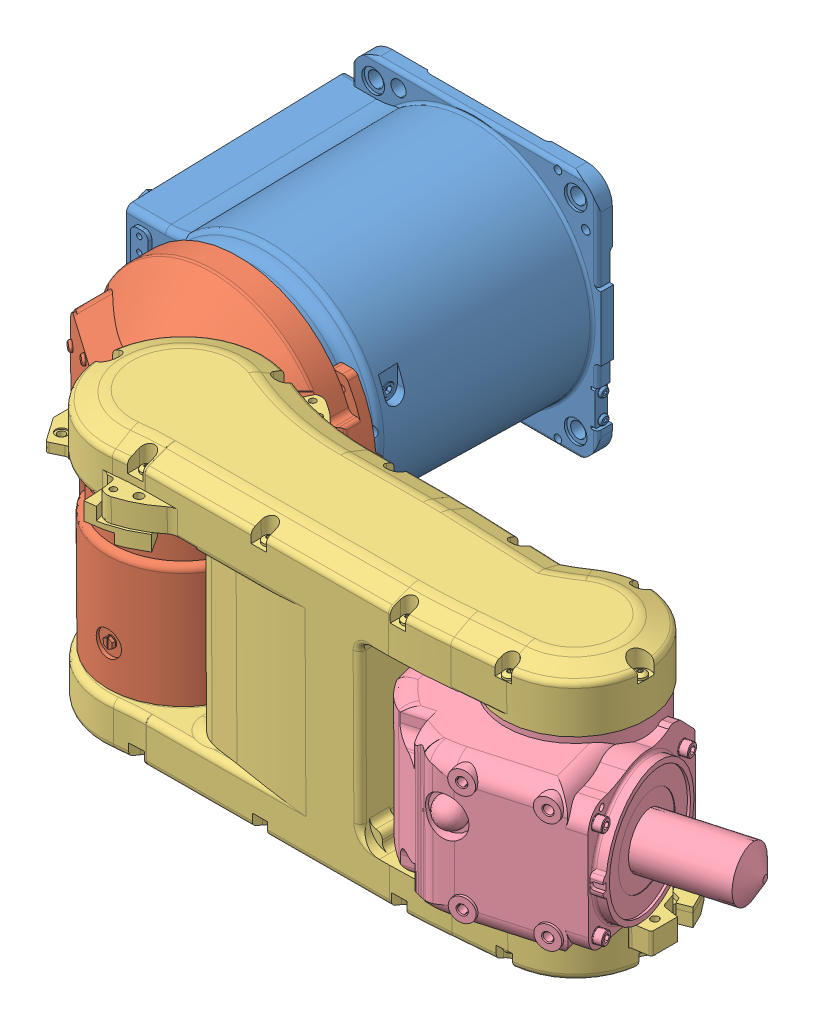
SolidWorks assembly EPSONS5_1, configuration Default. Lengths in mm.
Overall size (699.22 221.61 438.52).
4 component instances, 4 part files, 8 mates.
Components (placement in the parent):
- S5_BASE-1: S5_BASE [Default] at origin size (250.2 197 204.01)
- S5_ARM1-1: S5_ARM1 [Default] at (87.999 0.4259 126.5) x (0.999988 0.004839 0) z (-0.004839 0.999988 0) size (245.28 204.35 187)
- S5_ARM2-1: S5_ARM2 [Default] at (397.9856 3.926 126.6065) x (0.999988 0.004839 0.000344) z (-0.004839 0.999988 0) size (450 164.19 219.43)
- S5_ARM3-1: S5_ARM3 [Default] at (547.9742 6.6518 126.6061) x (0.999988 0.004839 -0.000003) z (0.000003 0 1) size (256.96 134.01 164.65)
Mates (geometry in assembly coordinates):
- Concentric4: concentric: cylinder of S5_BASE-1 through (0 0 -192.5) axis (0 0 1) radius 82
- Coincident4: coincident: plane of S5_BASE-1 through (0 0 0) normal (0 0 1)
- Coincident5: coincident anti-aligned: plane of S5_BASE-1 through (0 0 0) normal (0 0 1); plane of S5_ARM1-1 through (0 0 0) normal (0 0 -1)
- Concentric5: concentric aligned: cylinder of S5_BASE-1 through (0 0 -192.5) axis (0 0 1) radius 75; cylinder of S5_ARM1-1 through (0 0 -4.5) axis (0 0 1) radius 75
- Coincident6: coincident anti-aligned: plane of S5_ARM1-1 through (88.2942 -60.5734 181.5) normal (0.004839 -0.999988 0); plane of S5_ARM2-1 through (88.2942 -60.5734 126.5) normal (-0.004839 0.999988 0)
- Concentric6: concentric aligned: cylinder of S5_ARM1-1 through (88.2942 -60.5734 126.5) axis (-0.004839 0.999988 0) radius 55; cylinder of S5_ARM2-1 through (88.3547 -73.0733 126.5) axis (-0.004839 0.999988 0) radius 50
- Coincident11: coincident anti-aligned: plane of S5_ARM2-1 through (397.6614 70.9252 126.6065) normal (0.004839 -0.999988 0); plane of S5_ARM3-1 through (397.6614 70.9252 126.6065) normal (-0.004839 0.999988 0)
- Concentric8: concentric aligned: cylinder of S5_ARM2-1 through (398.3292 -67.0732 126.6065) axis (-0.004839 0.999988 0) radius 50; cylinder of S5_ARM3-1 through (398.3099 -63.0732 126.6065) axis (-0.004839 0.999988 0) radius 50
